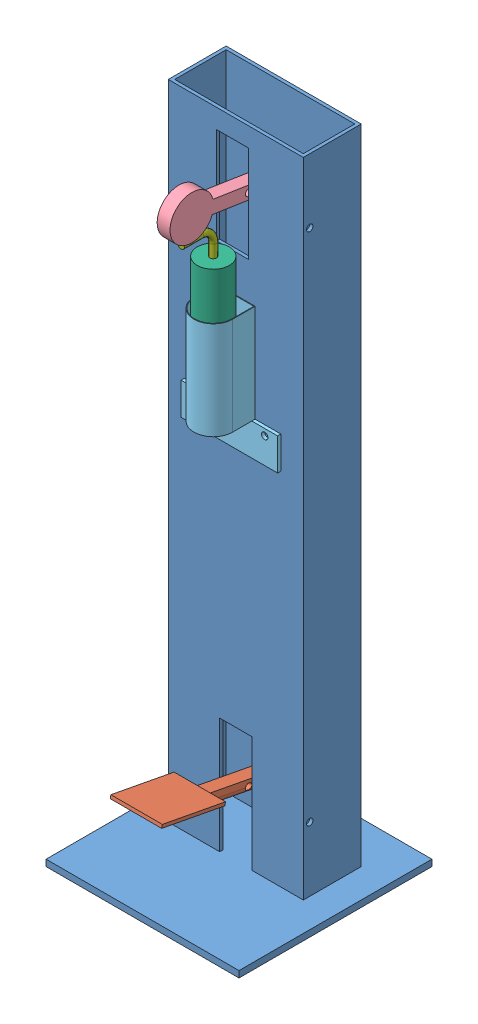
SolidWorks assembly project 1, configuration Default. Lengths in mm.
Overall size (300 1010 313.88).
7 component instances, 7 part files, 9 mates.
Components (placement in the parent):
- Part2^project 1-1: Part2^project 1 [Default] at origin size (300 1010 300) (virtual)
- Part5^project 1-1: Part5^project 1 [Default] at (0 -31.1117 -1.3865) x (1 0 0) z (0 0.186433 0.982468) size (80 25 230) (virtual)
- Part6^project 1-1: Part6^project 1 [Default] at (0 0.0447 -0.295) x (1 0 0) z (0 0.011765 0.999931) size (30 820 20) (virtual)
- Part7^project 1-1: Part7^project 1 [Default] at (-0.1436 -33.348 -32.0825) x (1 0 0) z (0 0.152916 0.988239) size (20 67.77 182.67) (virtual)
- Part8^project 1-1: Part8^project 1 [Default] at origin size (150 202 65) (virtual)
- Part9^project 1-1: Part9^project 1 [Default] at origin size (50 220 50) (virtual)
- Part10^project 1-1: Part10^project 1 [Default] at (0 25.5207 1.2045) size (10 65 55) (virtual)
Mates (geometry in assembly coordinates):
- Concentric1: concentric aligned: cylinder of Part2^project 1-1 through (895 110 -5) axis (-1 0 0) radius 5; cylinder of Part5^project 1-1 through (10 110 -5) axis (-1 0 0) radius 5
- Width1: width anti-aligned: plane of Part2^project 1-1 through (-105 1010 -80) normal (-1 0 0); plane of Part2^project 1-1 through (105 1010 -80) normal (1 0 0); plane of Part5^project 1-1 through (10 -31.1117 -1.3865) normal (1 0 0); plane of Part5^project 1-1 through (-10 -31.1117 -1.3865) normal (-1 0 0)
- Concentric6: concentric aligned: cylinder of Part5^project 1-1 through (10 102.4096 -45) axis (-1 0 0) radius 5; cylinder of Part6^project 1-1 through (15 102.4096 -45) axis (-1 0 0) radius 5
- Coincident3: coincident anti-aligned: plane of Part5^project 1-1 through (-10 -31.1117 -1.3865) normal (-1 0 0); plane of Part6^project 1-1 through (-10 130.4389 -35.3291) normal (1 0 0)
- Concentric7: concentric aligned: cylinder of Part2^project 1-1 through (895 910 -5) axis (-1 0 0) radius 5; cylinder of Part7^project 1-1 through (9.8564 910 -5) axis (-1 0 0) radius 5
- Concentric8: concentric aligned: cylinder of Part6^project 1-1 through (15 902.3542 -54.412) axis (-1 0 0) radius 5; cylinder of Part7^project 1-1 through (9.8564 902.3542 -54.412) axis (-1 0 0) radius 5
- Concentric9: concentric anti-aligned: cylinder of Part9^project 1-1 through (0 792 40) axis (0 1 0) radius 5; cylinder of Part10^project 1-1 through (0 861.5423 40) axis (0 -1 0) radius 5
- Coincident6: coincident aligned: plane of Part10^project 1-1 through (0 25.5207 1.2045) normal (1 0 0); plane of assembly through (0 0 0) normal (1 0 0)
- Tangent4: tangent anti-aligned: cylinder of Part7^project 1-1 through (9.8564 920.428 83.2282) axis (-1 0 0) radius 33.8857; cylinder of Part10^project 1-1 through (0 881.5423 90) axis (0 0 -1) radius 5
